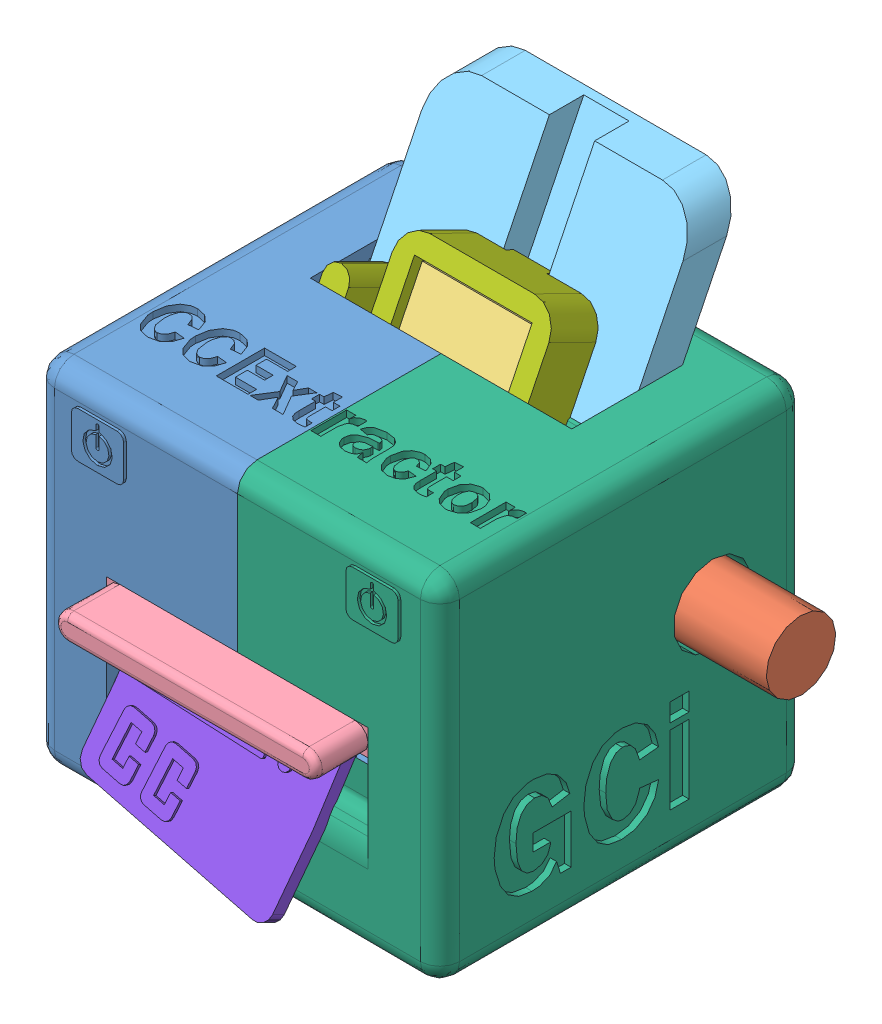
SolidWorks assembly [A] Functional-Multi Color Glue , configuration Default. Lengths in mm.
Overall size (479.65 504.73 418.41).
8 component instances, 8 part files, 19 mates.
Components (placement in the parent):
- [P] Functional-Multi Color Glue - Main Body Left-1: [P] Functional-Multi Color Glue - Main Body Left [Default] at (293.0443 -24.6756 171.0885) size (196.85 342.9 358.14)
- [P] Functional-Multi Color Glue - Turner-1: [P] Functional-Multi Color Glue - Turner [Default] at (311.0443 172.1939 261.8246) x (-1 0 0) z (0 -0.999142 -0.04141) size (304.8 103.43 108)
- [P] Functional-Multi Color Glue - TV Background-1: [P] Functional-Multi Color Glue - TV Background [Default] at (295.5842 248.5327 319.0556) x (0 -0.897542 0.440929) z (-1 0 0) size (209.55 25.4 107.95)
- [P] Functional-Multi Color Glue - Bill-1: [P] Functional-Multi Color Glue - Bill [Default] at (293.0443 -24.6756 171.0885) size (304.8 88.9 90.8)
- [P] Functional-Multi Color Glue - Tray'-1: [P] Functional-Multi Color Glue - Tray' [Default] at (293.0443 -25.337 169.7421) size (304.8 180.81 123.02)
- [P] Functional-Multi Color Glue - Main Body Right-1: [P] Functional-Multi Color Glue - Main Body Right [Default] at (287.9643 -24.6756 171.0885) size (245.11 342.9 358.14)
- [P] Functional-Multi Color Glue - TV-1: [P] Functional-Multi Color Glue - TV [Default] at (250.7672 176.9945 371.3896) x (0 -0.897542 0.440929) z (-1 0 0) size (330.2 79.8 203.2)
- [P] Functional-Multi Color Glue - Script-1: [P] Functional-Multi Color Glue - Script [Default] at (250.7672 176.9945 371.3896) x (0 -0.897542 0.440929) z (-1 0 0) size (213.82 123.19 217.08)
Mates (geometry in assembly coordinates):
- Coincident9: coincident anti-aligned: plane of [P] Functional-Multi Color Glue - Main Body Left-1 through (271.0443 448.796 167.6958) normal (1 0 0); plane of [P] Functional-Multi Color Glue - Turner-1 through (271.0443 172.1939 261.8246) normal (-1 0 0)
- Concentric1: concentric aligned: cylinder of [P] Functional-Multi Color Glue - Main Body Left-1 through (91.4392 172.1939 261.8246) axis (1 0 0) radius 63.5; cylinder of [P] Functional-Multi Color Glue - Turner-1 through (271.0443 172.1939 261.8246) axis (1 0 0) radius 33.749
- Coincident18: coincident anti-aligned: plane of [P] Functional-Multi Color Glue - Main Body Left-1 through (38.9701 229.3244 511.6885) normal (0 0 -1); plane of [P] Functional-Multi Color Glue - Bill-1 through (96.1943 165.8244 511.6885) normal (0 0 1)
- Coincident19: coincident anti-aligned: plane of [P] Functional-Multi Color Glue - Main Body Left-1 through (38.9701 229.3244 486.6885) normal (0 -1 0); plane of [P] Functional-Multi Color Glue - Bill-1 through (96.1943 229.3244 511.6885) normal (0 1 0)
- Coincident20: coincident anti-aligned: plane of [P] Functional-Multi Color Glue - Main Body Left-1 through (140.6443 -24.6756 171.0885) normal (1 0 0); plane of [P] Functional-Multi Color Glue - Bill-1 through (140.6443 -24.6756 171.0885) normal (-1 0 0)
- Coincident21: coincident anti-aligned: plane of [P] Functional-Multi Color Glue - Main Body Left-1 through (104.7518 263.7554 247.9034) normal (0 0.440929 0.897542); plane of [P] Functional-Multi Color Glue - Tray'-1 through (420.0443 317.563 221.4697) normal (0 -0.440929 -0.897542)
- Coincident22: coincident anti-aligned: plane of [P] Functional-Multi Color Glue - Main Body Left-1 through (-52.646 267.9883 256.5198) normal (0 0.897542 -0.440929); plane of [P] Functional-Multi Color Glue - Tray'-1 through (96.1943 267.3269 255.1735) normal (0 -0.897542 0.440929)
- Coincident23: coincident anti-aligned: plane of [P] Functional-Multi Color Glue - Main Body Left-1 through (140.6443 -24.6756 171.0885) normal (1 0 0); plane of [P] Functional-Multi Color Glue - Tray'-1 through (140.6443 -25.337 169.7421) normal (-1 0 0)
- Concentric2: concentric aligned: cylinder of [P] Functional-Multi Color Glue - Main Body Left-1 through (239.7043 285.5288 493.9928) axis (1 0 0) radius 25.4; cylinder of [P] Functional-Multi Color Glue - Main Body Right-1 through (244.7843 285.5288 493.9928) axis (1 0 0) radius 25.4
- Concentric3: concentric aligned: cylinder of [P] Functional-Multi Color Glue - Main Body Left-1 through (239.7043 8.02 203.7841) axis (1 0 0) radius 25.4; cylinder of [P] Functional-Multi Color Glue - Main Body Right-1 through (244.7843 8.02 203.7841) axis (1 0 0) radius 25.4
- Coincident24: coincident anti-aligned: plane of [P] Functional-Multi Color Glue - Main Body Left-1 through (293.0443 -24.6756 171.0885) normal (1 0 0); plane of [P] Functional-Multi Color Glue - Main Body Right-1 through (293.0443 -24.6756 171.0885) normal (-1 0 0)
- Width1: width anti-aligned: plane of [P] Functional-Multi Color Glue - TV-1 through (238.4342 356.622 294.2549) normal (1 0 0); plane of [P] Functional-Multi Color Glue - TV-1 through (352.7342 356.622 294.2549) normal (-1 0 0); plane of [P] Functional-Multi Color Glue - TV Background-1 through (241.6092 353.7723 295.6549) normal (-1 0 0); plane of [P] Functional-Multi Color Glue - TV Background-1 through (349.5592 165.6923 388.0515) normal (1 0 0)
- Width2: width anti-aligned: plane of [P] Functional-Multi Color Glue - TV Background-1 through (349.5592 353.7723 295.6549) normal (0 0.897542 -0.440929); plane of [P] Functional-Multi Color Glue - TV Background-1 through (241.6092 165.6923 388.0515) normal (0 -0.897542 0.440929); plane of [P] Functional-Multi Color Glue - TV-1 through (238.4342 356.622 294.2549) normal (0 -0.897542 0.440929); plane of [P] Functional-Multi Color Glue - TV-1 through (238.4342 162.8426 389.4514) normal (0 0.897542 -0.440929)
- Coincident28: coincident anti-aligned: plane of [P] Functional-Multi Color Glue - TV Background-1 through (295.5842 248.5327 319.0556) normal (0 -0.440929 -0.897542); plane of [P] Functional-Multi Color Glue - TV-1 through (250.7672 170.1916 357.5417) normal (0 0.440929 0.897542)
- Width3: width aligned: plane of [P] Functional-Multi Color Glue - TV-1 through (313.0443 341.3339 219.9308) normal (1 0 0); plane of [P] Functional-Multi Color Glue - TV-1 through (273.0443 341.3339 219.9308) normal (-1 0 0); plane of [P] Functional-Multi Color Glue - Tray'-1 through (271.0443 448.1346 166.3495) normal (1 0 0); plane of [P] Functional-Multi Color Glue - Tray'-1 through (315.0443 448.1346 166.3495) normal (-1 0 0)
- Coincident29: coincident anti-aligned: plane of [P] Functional-Multi Color Glue - Tray'-1 through (420.0443 317.563 263.919) normal (0 0.440929 0.897542); plane of [P] Functional-Multi Color Glue - TV-1 through (181.2842 240.133 301.9574) normal (0 -0.440929 -0.897542)
- Coincident30: coincident anti-aligned: plane of [P] Functional-Multi Color Glue - TV-1 through (181.2842 148.5443 403.5505) normal (0 -0.897542 0.440929); plane of [P] Functional-Multi Color Glue - Script-1 through (244.7842 79.9681 263.9586) normal (0 0.897542 -0.440929)
- Coincident31: coincident anti-aligned: plane of [P] Functional-Multi Color Glue - TV-1 through (295.5842 108.9474 380.5538) normal (-0.447214 0.394379 0.802786); plane of [P] Functional-Multi Color Glue - Script-1 through (295.5842 225.7417 323.1771) normal (0.447214 -0.394379 -0.802786)
- Coincident32: coincident: plane of [P] Functional-Multi Color Glue - TV-1 through (244.7842 120.147 403.3513) normal (0.447214 0.394379 0.802786); line of [P] Functional-Multi Color Glue - Script-1 through (244.7842 142.9445 392.1517) axis (0 -0.897542 0.440929)
